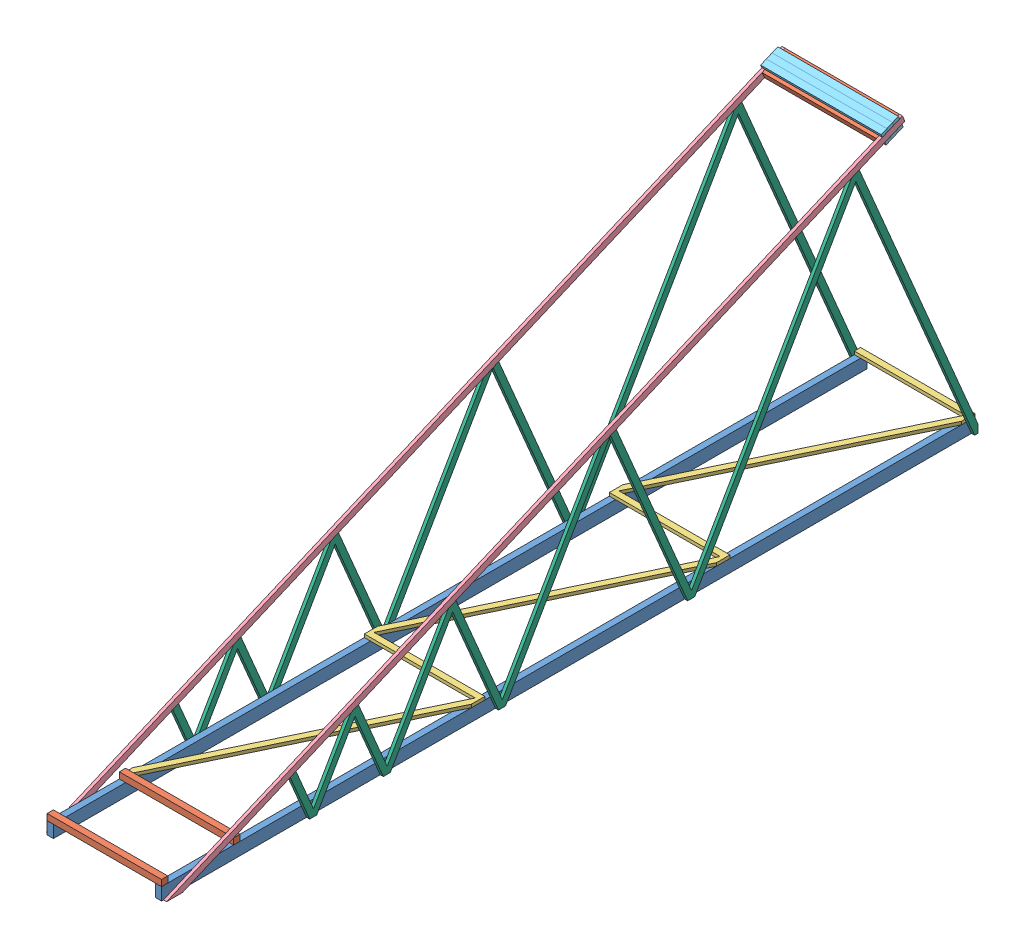
SolidWorks assembly V2 1-1, configuration Default. Lengths in mm.
Overall size (61.52 160.34 415).
20 component instances, 7 part files, 59 mates.
Components (placement in the parent):
- CompressionBeam-1: CompressionBeam [Default] at (128.4141 212.2584 116.772) size (3.17 6.35 415)
- CompressionBeam-2: CompressionBeam [Default] at (73.2391 212.2584 116.772) size (3.17 6.35 415)
- Part2^V2 1-1-1: Part2^V2 1-1 [Default] at (73.2391 212.2584 116.772) x (0 0 1) z (-1 0 0) (virtual)
- CompressionHorizontalBrace-1: CompressionHorizontalBrace [Default] at (73.2391 221.7834 531.772) x (0 -1 0) z (1 0 0) size (3.17 3.17 58.35)
- CompressionHorizontalBrace-2: CompressionHorizontalBrace [Default] at (73.2391 221.7834 494.947) x (0 -1 0) z (1 0 0) size (3.17 3.17 58.35)
- Part4^V2 1-1-1: Part4^V2 1-1 [Default] at (128.4141 218.6084 116.772) x (1 0 0) z (0 1 0) size (58.35 375 1.59) (virtual)
- Part5^V2 1-1-1: Part5^V2 1-1 [Default] at (73.2391 212.2584 116.772) x (0 0 1) z (-1 0 0) size (376.7 159.5 1.59) (virtual)
- CompressionHorizontalBrace-3: CompressionHorizontalBrace [Default] at (73.2391 369.274 161.1687) x (0 -0.920393 -0.390995) z (1 0 0) size (3.17 3.17 58.35)
- CompressionHorizontalBrace-4: CompressionHorizontalBrace [Default] at (73.2391 370.5154 158.2464) x (0 -0.920393 -0.390995) z (1 0 0) size (3.17 3.17 58.35)
- CompressionHorizontalBrace-5: CompressionHorizontalBrace [Default] at (73.2391 368.0326 164.0909) x (0 -0.920393 -0.390995) z (1 0 0) size (3.17 3.17 58.35)
- CompressionHorizontalBrace-6: CompressionHorizontalBrace [Default] at (73.2391 366.7912 167.0132) x (0 -0.920393 -0.390995) z (1 0 0) size (3.17 3.17 58.35)
- Part5^V2 1-1-2: Part5^V2 1-1 [Default] at (133.1766 212.2584 116.772) x (0 0 1) z (-1 0 0) size (376.7 159.5 1.59) (virtual)
- Part6^V2 1-1-1: Part6^V2 1-1 [Default] at (73.2391 366.621 167.4137) x (1 0 0) z (0 0.920393 0.390995) size (61.52 3.18 1.59) (virtual)
- Part6^V2 1-1-2: Part6^V2 1-1 [Default] at (73.2391 367.8625 164.4915) x (1 0 0) z (0 0.920393 0.390995) size (61.52 3.18 1.59) (virtual)
- Part6^V2 1-1-3: Part6^V2 1-1 [Default] at (73.2391 369.1039 161.5693) x (1 0 0) z (0 0.920393 0.390995) size (61.52 3.18 1.59) (virtual)
- Part6^V2 1-1-4: Part6^V2 1-1 [Default] at (73.2391 364.7205 159.7071) x (1 0 0) z (0 0.920393 0.390995) size (61.52 3.18 1.59) (virtual)
- Part6^V2 1-1-5: Part6^V2 1-1 [Default] at (73.2391 363.4791 162.6294) x (1 0 0) z (0 0.920393 0.390995) size (61.52 3.18 1.59) (virtual)
- Part6^V2 1-1-6: Part6^V2 1-1 [Default] at (73.2391 362.2377 165.5516) x (1 0 0) z (0 0.920393 0.390995) size (61.52 3.18 1.59) (virtual)
- Part7^V2 1-1-1: Part7^V2 1-1 [Default] at (131.5891 212.2584 116.772) x (0 0 -1) z (1 0 0) size (350.91 146.69 1.59) (virtual)
- Part7^V2 1-1-2: Part7^V2 1-1 [Default] at (71.6516 212.2584 116.772) x (0 0 -1) z (1 0 0) size (350.91 146.69 1.59) (virtual)
Mates (geometry in assembly coordinates):
- Distance1: distance = 52 mm: plane of CompressionBeam-1 through (128.4141 212.2584 531.772) normal (-1 0 0); plane of CompressionBeam-2 through (76.4141 212.2584 531.772) normal (1 0 0)
- Coincident2: coincident: plane of CompressionBeam-1 through (128.4141 212.2584 531.772) normal (0 0 1); plane of CompressionBeam-2 through (73.2391 212.2584 531.772) normal (0 0 1)
- InPlace1: in place: plane of ? through (73.2391 213.1549 521.772) normal (-1 0 0); plane of ? through (73.2391 0 0) normal (-1 0 0); moOrthogonalPlaneRef_w of ? through (73.2391 213.1549 521.772) normal (-1 0 0); plane of ? through (73.2391 0 0) normal (0 1 0); plane of ? through (73.2391 213.1549 521.772) normal (-1 0 0); plane of ? through (73.2391 0 0) normal (0 0 1); plane of CompressionBeam-2 through (73.2391 212.2584 531.772) normal (-1 0 0); unknown of ?
- Coincident3: coincident: plane of CompressionBeam-2; plane of Part2^V2 1-1-1
- Coincident4: coincident: moOrthogonalPlaneRef_w of CompressionBeam-2 through (73.2391 212.2584 116.772) normal (0 1 0); plane of Part2^V2 1-1-1 through (73.2391 212.2584 116.772) normal (0 1 0)
- Coincident5: coincident: moOrthogonalPlaneRef_w of CompressionBeam-2 through (73.2391 212.2584 116.772) normal (0 0 -1); plane of Part2^V2 1-1-1 through (73.2391 212.2584 116.772) normal (0 0 1)
- Coincident6: coincident: plane of CompressionBeam-1 through (131.5891 212.2584 531.772) normal (1 0 0); plane of CompressionHorizontalBrace-1 through (131.5891 221.7834 531.772) normal (1 0 0)
- Coincident7: coincident: plane of CompressionBeam-1 through (128.4141 218.6084 531.772) normal (0 1 0); plane of CompressionHorizontalBrace-1 through (131.5891 218.6084 531.772) normal (0 -1 0)
- Coincident8: coincident: plane of CompressionBeam-1 through (128.4141 212.2584 531.772) normal (0 0 1); plane of CompressionHorizontalBrace-1 through (131.5891 221.7834 531.772) normal (0 0 1)
- Coincident9: coincident: plane of CompressionBeam-2 through (73.2391 218.6084 531.772) normal (0 1 0); plane of CompressionHorizontalBrace-1 through (131.5891 218.6084 531.772) normal (0 -1 0)
- Coincident10: coincident: plane of CompressionBeam-2 through (73.2391 212.2584 531.772) normal (-1 0 0); plane of CompressionHorizontalBrace-2 through (73.2391 221.7834 494.947) normal (-1 0 0)
- Coincident11: coincident: plane of CompressionBeam-2 through (73.2391 218.6084 531.772) normal (0 1 0); plane of CompressionHorizontalBrace-2 through (131.5891 218.6084 494.947) normal (0 -1 0)
- InPlace2: in place: plane of CompressionBeam-1 through (128.4141 218.6084 521.772) normal (0 1 0); plane of ? through (0 218.6084 0) normal (0 1 0); plane of CompressionBeam-1 through (128.4141 218.6084 521.772) normal (0 1 0); plane of ? through (0 218.6084 0) normal (0 0 -1); plane of CompressionBeam-1 through (128.4141 218.6084 521.772) normal (0 1 0); plane of ? through (0 218.6084 0) normal (1 0 0); plane of CompressionBeam-1 through (128.4141 218.6084 531.772) normal (0 1 0); unknown of Part4^V2 1-1-1
- Coincident13: coincident: plane of ?; plane of Part4^V2 1-1-1
- Coincident14: coincident: moOrthogonalPlaneRef_w of CompressionBeam-1 through (128.4141 218.6084 116.772) normal (0 0 -1); plane of Part4^V2 1-1-1 through (128.4141 218.6084 116.772) normal (0 0 -1)
- Coincident15: coincident: moOrthogonalPlaneRef_w of CompressionBeam-1 through (128.4141 218.6084 116.772) normal (-1 0 0); plane of Part4^V2 1-1-1 through (128.4141 218.6084 116.772) normal (1 0 0)
- InPlace3: in place: plane of CompressionBeam-2 through (73.2391 212.2584 521.772) normal (-1 0 0); plane of ? through (73.2391 0 0) normal (-1 0 0); plane of CompressionBeam-2 through (73.2391 212.2584 521.772) normal (-1 0 0); plane of ? through (73.2391 0 0) normal (0 1 0); plane of CompressionBeam-2 through (73.2391 212.2584 521.772) normal (-1 0 0); plane of ? through (73.2391 0 0) normal (0 0 1); plane of CompressionBeam-2 through (73.2391 212.2584 531.772) normal (-1 0 0); unknown of ?
- Coincident16: coincident: plane of CompressionBeam-2; plane of Part5^V2 1-1-1
- Coincident17: coincident: moOrthogonalPlaneRef_w of CompressionBeam-2 through (73.2391 212.2584 116.772) normal (0 1 0); plane of Part5^V2 1-1-1 through (73.2391 212.2584 116.772) normal (0 1 0)
- Coincident18: coincident: moOrthogonalPlaneRef_w of CompressionBeam-2 through (73.2391 212.2584 116.772) normal (0 0 -1); plane of Part5^V2 1-1-1 through (73.2391 212.2584 116.772) normal (0 0 1)
- Coincident19: coincident: plane of CompressionHorizontalBrace-2 through (131.5891 221.7834 491.772) normal (0 0 -1); plane of Part4^V2 1-1-1 through (128.4141 220.1959 491.772) normal (0 0 1)
- Coincident20: coincident: plane of Part5^V2 1-1-1 through (73.2391 212.2584 116.772) normal (1 0 0); plane of CompressionHorizontalBrace-4 through (73.2391 370.5154 158.2464) normal (-1 0 0)
- Coincident21: coincident: plane of Part5^V2 1-1-1 through (73.2391 212.2584 116.772) normal (1 0 0); plane of CompressionHorizontalBrace-3 through (73.2391 369.274 161.1687) normal (-1 0 0)
- Coincident22: coincident: plane of Part5^V2 1-1-1 through (73.2391 212.2584 116.772) normal (1 0 0); plane of CompressionHorizontalBrace-5 through (73.2391 368.0326 164.0909) normal (-1 0 0)
- Coincident23: coincident: plane of Part5^V2 1-1-1 through (73.2391 212.2584 116.772) normal (1 0 0); plane of CompressionHorizontalBrace-6 through (73.2391 366.7912 167.0132) normal (-1 0 0)
- Coincident24: coincident: plane of CompressionHorizontalBrace-5 through (131.5891 368.0326 164.0909) normal (0 -0.390995 0.920393); plane of CompressionHorizontalBrace-6 through (131.5891 368.0326 164.0909) normal (0 0.390995 -0.920393)
- Coincident25: coincident: plane of CompressionHorizontalBrace-5 through (131.5891 365.1104 162.8495) normal (0 -0.920393 -0.390995); plane of CompressionHorizontalBrace-6 through (131.5891 363.869 165.7718) normal (0 -0.920393 -0.390995)
- Coincident26: coincident: plane of CompressionHorizontalBrace-3 through (131.5891 366.3518 159.9273) normal (0 -0.920393 -0.390995); plane of CompressionHorizontalBrace-5 through (131.5891 365.1104 162.8495) normal (0 -0.920393 -0.390995)
- Coincident27: coincident: plane of CompressionHorizontalBrace-3 through (131.5891 366.3518 159.9273) normal (0 -0.920393 -0.390995); plane of CompressionHorizontalBrace-4 through (131.5891 367.5932 157.005) normal (0 -0.920393 -0.390995)
- Coincident28: coincident: plane of CompressionHorizontalBrace-3 through (131.5891 369.274 161.1687) normal (0 -0.390995 0.920393); plane of CompressionHorizontalBrace-5 through (131.5891 369.274 161.1687) normal (0 0.390995 -0.920393)
- Coincident29: coincident: plane of CompressionHorizontalBrace-3 through (131.5891 370.5154 158.2464) normal (0 0.390995 -0.920393); plane of CompressionHorizontalBrace-4 through (131.5891 370.5154 158.2464) normal (0 -0.390995 0.920393)
- Coincident30: coincident: plane of Part5^V2 1-1-1 through (73.2391 222.7683 92.0319) normal (0 0.390995 -0.920393); plane of CompressionHorizontalBrace-4 through (131.5891 371.7568 155.3242) normal (0 0.390995 -0.920393)
- Coincident31: coincident: plane of Part5^V2 1-1-1 through (71.6516 358.3247 178.8228) normal (0 -0.920393 -0.390995); plane of CompressionHorizontalBrace-4 through (131.5891 367.5932 157.005) normal (0 -0.920393 -0.390995)
- Coincident32: coincident: plane of CompressionHorizontalBrace-4 through (131.5891 371.7568 155.3242) normal (0 0.390995 -0.920393); plane of Part5^V2 1-1-2 through (133.1766 222.7683 92.0319) normal (0 0.390995 -0.920393)
- Coincident33: coincident: plane of CompressionHorizontalBrace-6 through (131.5891 366.7912 167.0132) normal (0 0.920393 0.390995); plane of Part5^V2 1-1-2 through (131.5891 361.247 180.0642) normal (0 0.920393 0.390995)
- Coincident34: coincident: plane of CompressionHorizontalBrace-6 through (131.5891 366.7912 167.0132) normal (1 0 0); plane of Part5^V2 1-1-2 through (131.5891 212.2584 116.772) normal (-1 0 0)
- Coincident38: coincident: plane of Part6^V2 1-1-1 through (71.6516 370.1144 163.2505) normal (-1 0 0); plane of Part6^V2 1-1-2 through (71.6516 371.3559 160.3283) normal (-1 0 0)
- Coincident39: coincident: plane of Part6^V2 1-1-2 through (71.6516 371.3559 160.3283) normal (-1 0 0); plane of Part6^V2 1-1-3 through (71.6516 372.5973 157.406) normal (-1 0 0)
- Coincident40: coincident: plane of Part6^V2 1-1-1 through (71.6516 370.1144 163.2505) normal (0 0.390995 -0.920393); plane of Part6^V2 1-1-2 through (71.6516 370.1144 163.2505) normal (0 -0.390995 0.920393)
- Coincident41: coincident: plane of Part6^V2 1-1-2 through (71.6516 371.3559 160.3283) normal (0 0.390995 -0.920393); plane of Part6^V2 1-1-3 through (71.6516 371.3559 160.3283) normal (0 -0.390995 0.920393)
- Coincident42: coincident: plane of CompressionHorizontalBrace-3 through (131.5891 369.274 161.1687) normal (0 0.920393 0.390995); plane of Part6^V2 1-1-2 through (73.2391 367.8625 164.4915) normal (0 -0.920393 -0.390995)
- Coincident43: coincident: plane of CompressionHorizontalBrace-4 through (131.5891 370.5154 158.2464) normal (0 0.920393 0.390995); plane of Part6^V2 1-1-3 through (73.2391 369.1039 161.5693) normal (0 -0.920393 -0.390995)
- Coincident44: coincident: plane of Part6^V2 1-1-4 through (71.6516 368.2139 155.5439) normal (-1 0 0); plane of Part6^V2 1-1-5 through (71.6516 366.9725 158.4662) normal (-1 0 0)
- Coincident45: coincident: plane of Part6^V2 1-1-5 through (71.6516 366.9725 158.4662) normal (-1 0 0); plane of Part6^V2 1-1-6 through (71.6516 365.7311 161.3884) normal (-1 0 0)
- Coincident46: coincident: plane of Part6^V2 1-1-5 through (71.6516 365.7311 161.3884) normal (0 -0.390995 0.920393); plane of Part6^V2 1-1-6 through (71.6516 365.7311 161.3884) normal (0 0.390995 -0.920393)
- Coincident47: coincident: plane of Part6^V2 1-1-4 through (71.6516 366.9725 158.4662) normal (0 -0.390995 0.920393); plane of Part6^V2 1-1-5 through (71.6516 366.9725 158.4662) normal (0 0.390995 -0.920393)
- Coincident48: coincident: plane of Part6^V2 1-1-4 through (73.2391 366.1816 160.3278) normal (0 0.920393 0.390995); plane of Part6^V2 1-1-5 through (73.2391 364.9402 163.2501) normal (0 0.920393 0.390995)
- Coincident49: coincident: plane of Part6^V2 1-1-5 through (73.2391 364.9402 163.2501) normal (0 0.920393 0.390995); plane of Part6^V2 1-1-6 through (73.2391 363.6988 166.1723) normal (0 0.920393 0.390995)
- Coincident50: coincident: plane of CompressionHorizontalBrace-6 through (131.5891 363.869 165.7718) normal (0 -0.920393 -0.390995); plane of Part6^V2 1-1-6 through (73.2391 363.6988 166.1723) normal (0 0.920393 0.390995)
- Coincident51: coincident: plane of Part6^V2 1-1-3 through (71.6516 372.5973 157.406) normal (-1 0 0); plane of Part6^V2 1-1-4 through (71.6516 368.2139 155.5439) normal (-1 0 0)
- Coincident52: coincident: plane of Part6^V2 1-1-1 through (71.6516 368.873 166.1728) normal (0 -0.390995 0.920393); plane of Part6^V2 1-1-6 through (71.6516 364.4897 164.3107) normal (0 -0.390995 0.920393)
- Distance3: distance = 1.5875 mm: plane of CompressionHorizontalBrace-6 through (131.5891 366.7912 167.0132) normal (0 -0.390995 0.920393); plane of Part6^V2 1-1-6 through (71.6516 364.4897 164.3107) normal (0 -0.390995 0.920393)
- InPlace5: in place: plane of CompressionBeam-1 through (131.5891 212.2584 531.772) normal (1 0 0); plane of ? through (131.5891 0 0) normal (1 0 0); plane of CompressionBeam-1 through (131.5891 212.2584 531.772) normal (1 0 0); plane of ? through (131.5891 0 0) normal (0 1 0); plane of CompressionBeam-1 through (131.5891 212.2584 531.772) normal (1 0 0); plane of ? through (131.5891 0 0) normal (0 0 -1); plane of CompressionBeam-1 through (131.5891 212.2584 531.772) normal (1 0 0); unknown of Part7^V2 1-1-1
- Coincident54: coincident: plane of ?; plane of Part7^V2 1-1-1
- Coincident55: coincident: moOrthogonalPlaneRef_w of CompressionBeam-1 through (131.5891 212.2584 116.772) normal (0 1 0); plane of Part7^V2 1-1-1 through (131.5891 212.2584 116.772) normal (0 1 0)
- Coincident56: coincident: moOrthogonalPlaneRef_w of CompressionBeam-1 through (131.5891 212.2584 116.772) normal (0 0 1); plane of Part7^V2 1-1-1 through (131.5891 212.2584 116.772) normal (0 0 -1)
- Coincident57: coincident: plane of CompressionBeam-2 through (73.2391 212.2584 531.772) normal (-1 0 0); plane of Part7^V2 1-1-2 through (73.2391 212.2584 116.772) normal (1 0 0)
- Coincident58: coincident: plane of CompressionBeam-2 through (73.2391 212.2584 531.772) normal (0 -1 0); plane of Part7^V2 1-1-2 through (73.2391 212.2584 116.772) normal (0 -1 0)
- Coincident59: coincident: plane of CompressionBeam-2 through (73.2391 212.2584 116.772) normal (0 0 -1); plane of Part7^V2 1-1-2 through (73.2391 212.2584 116.772) normal (0 0 -1)
